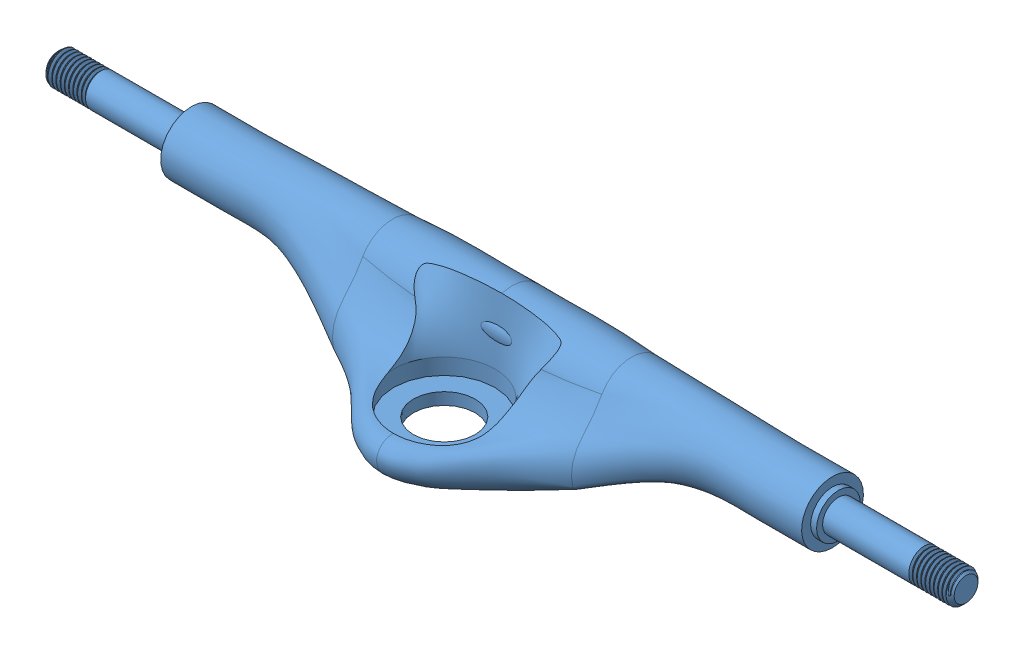
SolidWorks assembly hanger_assembly, configuration Default. Lengths in mm.
Overall size (228 45.83 61.52).
2 component instances, 2 part files, 2 mates.
Components (placement in the parent):
- hanger_uncut-1: hanger_uncut [Default] at origin size (228 45.83 61.52)
- cutout1-1: cutout1 [Default] at (0 -14 17.0091) size (40.43 24.01 29.37) (hidden)
Mates (geometry in assembly coordinates):
- Coincident4: coincident aligned: plane of cutout1-1 through (0 -14 17.0091) normal (1 0 0); plane of assembly through (0 0 0) normal (1 0 0)
- Coincident7: coincident anti-aligned: circle of hanger_uncut-1; circle of cutout1-1
